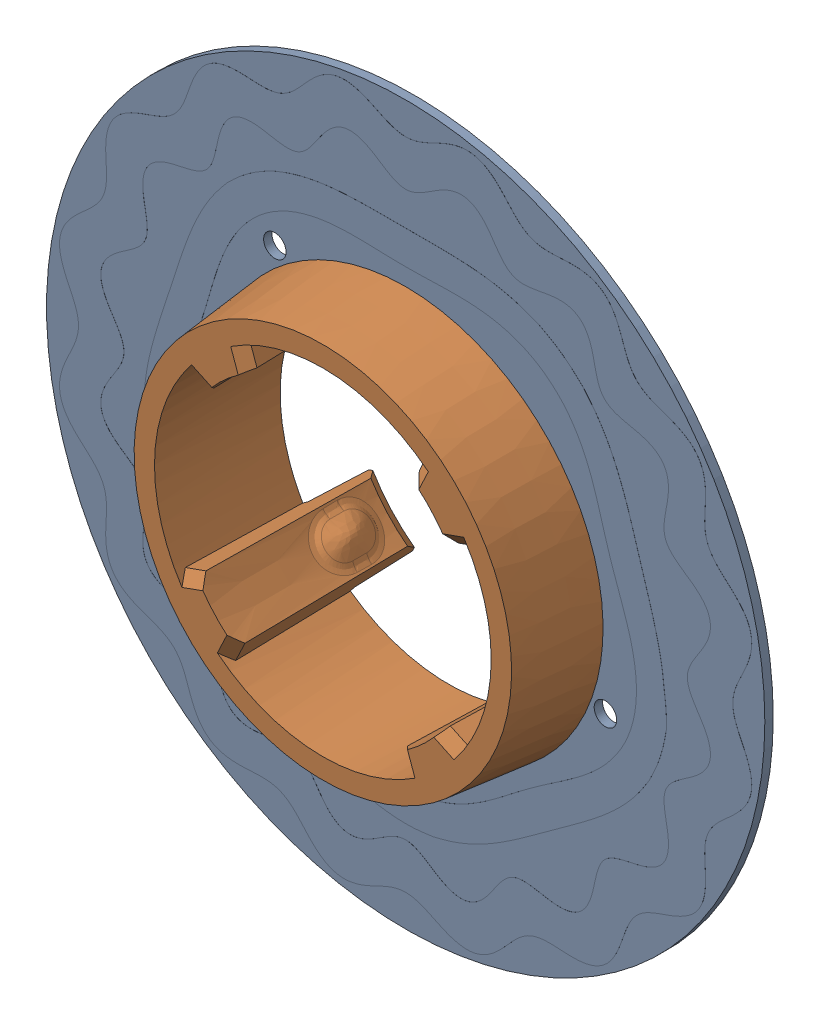
SolidWorks assembly CUI_DEVICES_overmold_rev_a, configuration Default. Lengths in mm.
Overall size (25.6 25.6 6.65).
2 component instances, 2 part files, 0 mates.
Components (placement in the parent):
- CUI_DEVICES_rotor_16f_5c_rev_d-1: CUI_DEVICES_rotor_16f_5c_rev_d [Default] at (-4.5895 18.9245 -10.5857) size (25.6 25.6 0.31)
- CUI_DEVICES_amt-overmold_hub-rev_a-1: CUI_DEVICES_amt-overmold_hub-rev_a [Default] at (-4.5895 18.9245 -10.5807) x (-0.941518 -0.336962 0) z (0 0 1) size (14.07 14.07 6.65)
